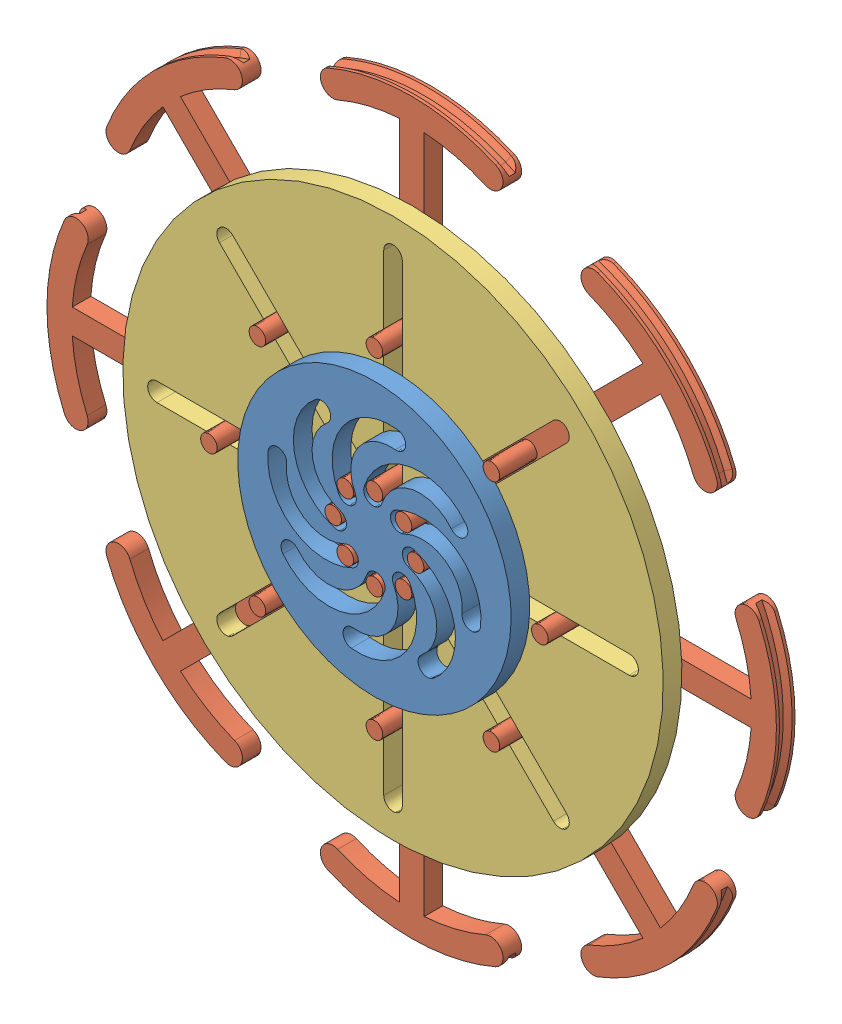
SolidWorks assembly asm_expanding-pulley, configuration Default. Lengths in mm.
Overall size (186.37 186.37 14.7).
10 component instances, 3 part files, 7 mates.
Components (placement in the parent):
- pulley-disc-1: pulley-disc [Default] at (0 -3.175 0) x (0.999268 0.038261 0) z (0 0 1) size (69.85 69.85 4.76)
- pulley-slider-1: pulley-slider [Default] at (0 7.3544 -9.525) size (46.69 85.83 14.7)
- pulley-slot-1: pulley-slot [Default] at (-5.08 1.27 -4.7625) x (1 0 0) z (0 -1 0) size (138.11 4.76 138.11)
- pulley-slider-3: pulley-slider [Default] at (-7.4454 4.2704 -9.525) x (0.707107 0.707107 0) z (0 0 1) size (46.69 85.83 14.7)
- pulley-slider-4: pulley-slider [Default] at (-10.5294 -3.175 -9.525) x (0 1 0) z (0 0 1) size (46.69 85.83 14.7)
- pulley-slider-5: pulley-slider [Default] at (-7.4454 -10.6204 -9.525) x (-0.707107 0.707107 0) z (0 0 1) size (46.69 85.83 14.7)
- pulley-slider-6: pulley-slider [Default] at (0 -13.7044 -9.525) x (-1 0 0) z (0 0 1) size (46.69 85.83 14.7)
- pulley-slider-7: pulley-slider [Default] at (7.4454 -10.6204 -9.525) x (-0.707107 -0.707107 0) z (0 0 1) size (46.69 85.83 14.7)
- pulley-slider-8: pulley-slider [Default] at (10.5294 -3.175 -9.525) x (0 -1 0) z (0 0 1) size (46.69 85.83 14.7)
- pulley-slider-9: pulley-slider [Default] at (7.4454 4.2704 -9.525) x (0.707107 -0.707107 0) z (0 0 1) size (46.69 85.83 14.7)
Mates (geometry in assembly coordinates):
- Coincident1: coincident aligned: plane of pulley-disc-1 through (0 -3.175 4.7625) normal (0 0 1); plane of pulley-slider-1 through (0 7.3544 4.7625) normal (0 0 1)
- Slot1: slot aligned: cylinder of pulley-slider-1 through (0 7.3544 4.7625) axis (0 0 -1) radius 2.1272; cylinder of pulley-disc-1 through (11.6222 2.5951 4.7625) axis (0 0 -1) radius 14.9401; cylinder of pulley-disc-1 through (-0.3644 6.343 4.7625) axis (0 0 -1) radius 2.3813
- Parallel1: parallel anti-aligned: plane of pulley-disc-1 through (0 -3.175 0) normal (0 0 -1); plane of pulley-slot-1 through (0 -3.175 0) normal (0 0 1)
- Slot2: slot aligned: cylinder of pulley-slider-1 through (0 7.3544 4.7625) axis (0 0 -1) radius 2.1272; plane of pulley-slot-1 through (2.3813 6.35 0) normal (-1 0 0); cylinder of pulley-slot-1 through (0 6.35 0) axis (0 0 -1) radius 2.3813
- Coincident3: coincident aligned: line of pulley-disc-1 through (0 -3.175 0) axis (0 0 1); line of pulley-slot-1 through (0 -3.175 -4.7625) axis (0 0 1)
- Coincident4: coincident anti-aligned: plane of pulley-disc-1 through (0 -3.175 0) normal (0 0 -1); plane of pulley-slot-1 through (0 -3.175 0) normal (0 0 1)
- Slot3: slot aligned: cylinder of pulley-slider-1 through (0 39.1044 4.7625) axis (0 0 -1) radius 2.1272; plane of pulley-slot-1 through (2.3813 6.35 0) normal (-1 0 0); cylinder of pulley-slot-1 through (0 6.35 0) axis (0 0 -1) radius 2.3813
